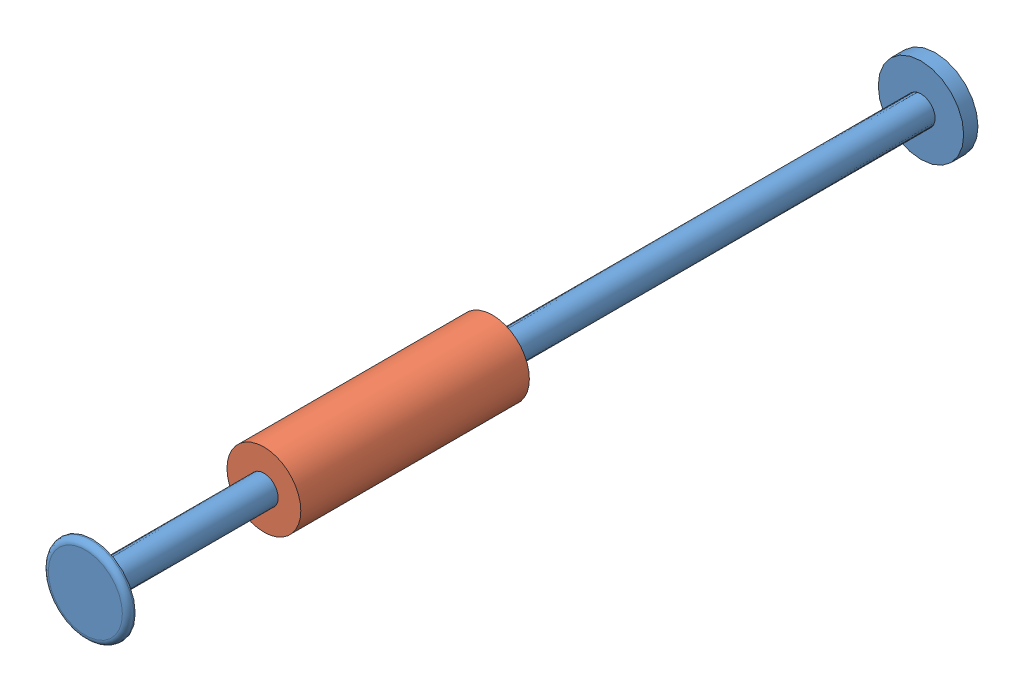
SolidWorks assembly Damper Assembly, configuration Default. Lengths in mm.
Overall size (38 38 377.82).
3 component instances, 3 part files, 0 mates.
Components (placement in the parent):
- Damper Rod-1: Damper Rod [Default] at (-301.9273 0 25.4) x (0 0 -1) z (1 0 0) size (377.82 38 38)
- Damper Cylinder-1: Damper Cylinder [Default] at origin size (32.82 32.82 101.6)
- O-Ring-1: O-Ring [Default] at (-492.1271 0 0) x (0 0 -1) z (1 0 0) size (1.27 26.37 26.37)
